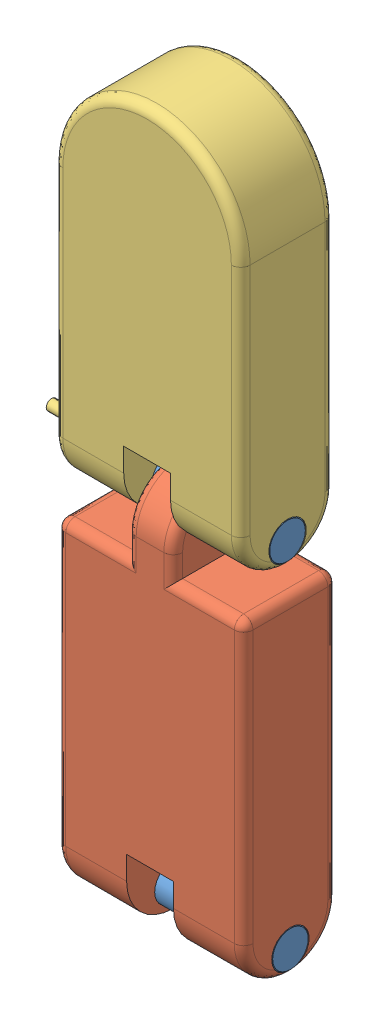
SolidWorks assembly Assem2, configuration Default. Lengths in mm.
Overall size (590.86 428.31 250.1).
4 component instances, 3 part files, 5 mates.
Components (placement in the parent):
- Whitepinthumb2-1: Whitepinthumb2 [Default] at (-78.1256 -9.3118 200) x (0 0 -1) z (1 0 0) size (40 40 200)
- bottomthumb2-1: bottomthumb2 [Default] at (21.8744 140.6882 250) size (202.17 424 100.1)
- Whitepinthumb2-2: Whitepinthumb2 [Default] at (-81.2159 366.6882 200) x (0 0 -1) z (1 0 0) size (40 40 200)
- topThumb2-1: topThumb2 [Default] at (18.7841 491.6882 250) size (223.09 400 100.1)
Mates (geometry in assembly coordinates):
- Concentric1: concentric: cylinder of assembly; cylinder of assembly; cylinder of Whitepinthumb2-1 through (121.8744 -9.3118 200) axis (-1 0 0) radius 20; cylinder of bottomthumb2-1 through (121.8744 -9.3118 200) axis (-1 0 0) radius 20
- Coincident1: coincident: plane of assembly; plane of assembly; plane of Whitepinthumb2-1 through (-78.1256 -9.3118 200) normal (-1 0 0); plane of bottomthumb2-1 through (-78.1256 315.6882 150) normal (-1 0 0)
- Concentric2: concentric: cylinder of assembly; cylinder of assembly; cylinder of bottomthumb2-1 through (-79.212 366.6882 200) axis (1 0 0) radius 20; cylinder of Whitepinthumb2-2 through (118.7841 366.6882 200) axis (-1 0 0) radius 20
- Concentric3: concentric: cylinder of assembly; cylinder of assembly; cylinder of Whitepinthumb2-2 through (118.7841 366.6882 200) axis (-1 0 0) radius 20; cylinder of topThumb2-1 through (118.7841 366.6882 200) axis (-1 0 0) radius 20
- Coincident2: coincident: plane of assembly; plane of assembly; plane of Whitepinthumb2-2 through (-81.2159 366.6882 200) normal (-1 0 0); plane of topThumb2-1 through (-81.2159 641.6882 150) normal (-1 0 0)
